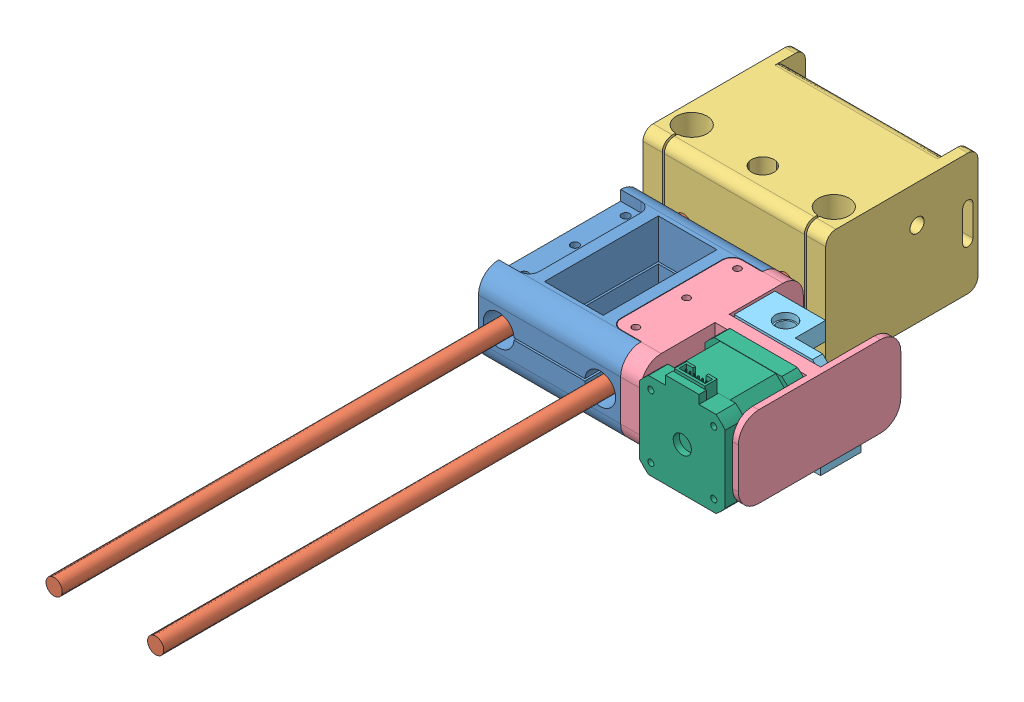
SolidWorks assembly Assem1, configuration Default. Lengths in mm.
Overall size (138 60 385).
7 component instances, 6 part files, 14 mates.
Components (placement in the parent):
- X_carriage_BQ_edit-1: X_carriage_BQ_edit [Default] at (31.7777 -13.9518 -58.1075) size (70 40 80)
- 8mmLinear375-1: 8mmLinear375 [Default] at (81.7777 -13.9518 -134.1378) x (0.630549 0.776149 0) z (0.776149 -0.630549 0) size (8 375 8)
- 8mmLinear375-2: 8mmLinear375 [Default] at (31.7777 -13.9518 -134.1378) x (0.505993 0.862538 0) z (0.862538 -0.505993 0) size (8 375 8)
- X_right-1: X_right [Default] at (11.7777 -13.9518 -101.6378) size (90 60 75)
- X_carriage_BQ_edit_suporte-1: X_carriage_BQ_edit_suporte [Default] at (91.7777 -33.9518 11.8925) x (0 0 -1) z (1 0 0) size (80 40 72.75)
- extruder-body-part-2: extruder-body-part [Predeterminado] at (136.5913 -191.9318 -31.3909) x (0 0 1) z (0 1 0) size (20 45 47.5)
- Extruder-motor-Nema-17-40mm-with-connector-2: Extruder-motor-Nema-17-40mm-with-connector [Predeterminado] at (-52.3523 -25.0171 -24.3909) x (0 0 1) z (1 0 0) size (60.1 48 42.3)
Mates (geometry in assembly coordinates):
- Concentric1: concentric anti-aligned: cylinder of X_carriage_BQ_edit-1 through (31.7777 -13.9518 21.8925) axis (0 0 -1) radius 7.6; cylinder of X_right-1 through (31.7777 -13.9518 -159.1378) axis (0 0 1) radius 4.1
- Concentric2: concentric anti-aligned: cylinder of X_carriage_BQ_edit-1 through (81.7777 -13.9518 21.8925) axis (0 0 -1) radius 7.6; cylinder of X_right-1 through (81.7777 -13.9518 -159.1378) axis (0 0 1) radius 4.1
- Concentric3: concentric anti-aligned: cylinder of 8mmLinear375-1 through (81.7777 -13.9518 240.8622) axis (0 0 -1) radius 4; cylinder of X_right-1 through (81.7777 -13.9518 -159.1378) axis (0 0 1) radius 4.1
- Concentric4: concentric anti-aligned: cylinder of 8mmLinear375-2 through (31.7777 -13.9518 240.8622) axis (0 0 -1) radius 4; cylinder of X_right-1 through (31.7777 -13.9518 -159.1378) axis (0 0 1) radius 4.1
- Coincident1: coincident aligned: plane of 8mmLinear375-1 through (81.7777 -13.9518 -134.1378) normal (0 0 -1); plane of X_right-1 through (101.7777 -38.9518 -134.1378) normal (0 0 -1)
- Coincident2: coincident aligned: plane of 8mmLinear375-1 through (81.7777 -13.9518 -134.1378) normal (0 0 -1); plane of 8mmLinear375-2 through (31.7777 -13.9518 -134.1378) normal (0 0 -1)
- Coincident3: coincident anti-aligned: plane of X_carriage_BQ_edit-1 through (91.7777 6.0482 21.8925) normal (1 0 0); plane of X_carriage_BQ_edit_suporte-1 through (91.7777 -3.9518 11.8925) normal (-1 0 0)
- Coincident4: coincident anti-aligned: plane of X_carriage_BQ_edit-1 through (81.7777 1.0482 6.8925) normal (0 1 0); plane of X_carriage_BQ_edit_suporte-1 through (76.7777 1.0482 11.8925) normal (0 -1 0)
- Coincident6: coincident aligned: plane of X_carriage_BQ_edit-1 through (31.7777 -13.9518 -58.1075) normal (0 0 -1); plane of X_carriage_BQ_edit_suporte-1 through (101.7777 -23.9518 -58.1075) normal (0 0 -1)
- Coincident14: coincident anti-aligned: plane of X_carriage_BQ_edit_suporte-1 through (101.7777 -3.9518 11.8925) normal (1 0 0); plane of extruder-body-part-2 through (101.7777 6.7587 -21.6075) normal (-1 0 0)
- Coincident15: coincident anti-aligned: plane of X_carriage_BQ_edit_suporte-1 through (146.7777 6.0482 -21.6075) normal (0 0 -1); plane of extruder-body-part-2 through (101.7777 -40.7413 -21.6075) normal (0 0 1)
- Concentric10: concentric anti-aligned: cylinder of X_carriage_BQ_edit_suporte-1 through (125.7777 -13.9518 23.3925) axis (0 0 -1) radius 11.5; cylinder of Extruder-motor-Nema-17-40mm-with-connector-2 through (125.7777 -13.9518 -14.6075) axis (0 0 1) radius 11
- Coincident16: coincident anti-aligned: plane of X_carriage_BQ_edit_suporte-1 through (146.7777 6.0482 -14.6075) normal (0 0 1); plane of Extruder-motor-Nema-17-40mm-with-connector-2 through (104.6277 -30.6018 -14.6075) normal (0 0 -1)
- Coincident17: coincident aligned: plane of extruder-body-part-2 through (142.7777 7.1982 -21.6075) normal (0 1 0); plane of Extruder-motor-Nema-17-40mm-with-connector-2 through (109.1277 7.1982 -6.8575) normal (0 1 0)
